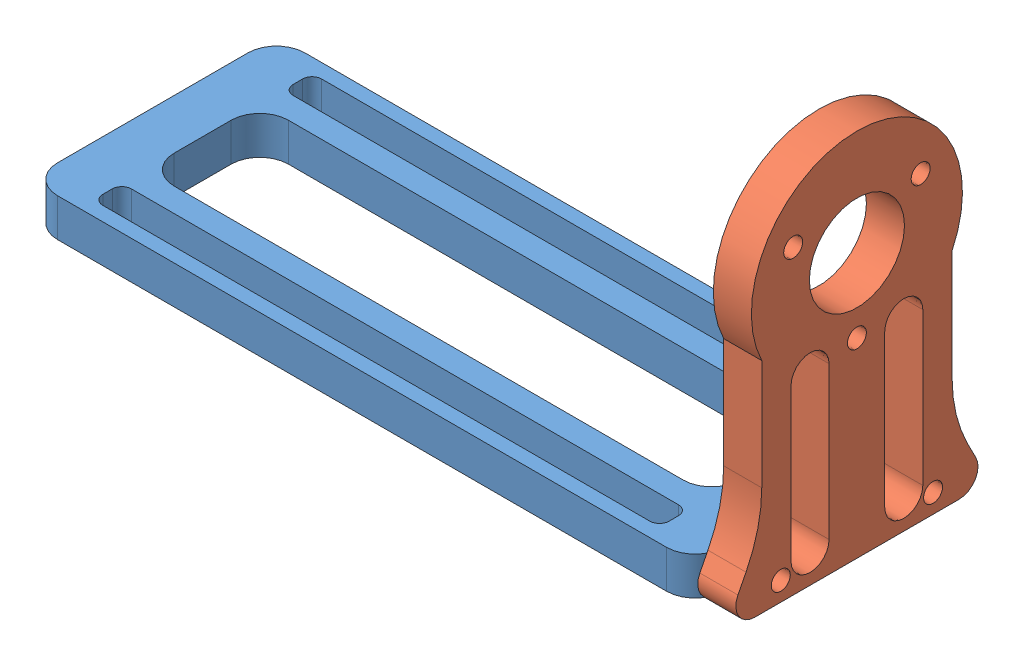
SolidWorks assembly Assem4, configuration Default. Lengths in mm.
Overall size (74 38.89 26).
2 component instances, 2 part files, 3 mates.
Components (placement in the parent):
- Camera hold-1: Camera hold [Default] at (24.9003 25.9441 60.2124) size (70 4 26)
- Motor1_below-1: Motor1_below [Default] at (59.9003 53.7377 60.2124) x (0 0 -1) z (1 0 0) size (25.45 38.89 4)
Mates (geometry in assembly coordinates):
- Concentric1: concentric: cylinder of Camera hold-1 through (54.9003 27.9441 68.2124) axis (1 0 0) radius 1; cylinder of Motor1_below-1 through (63.9003 27.9441 68.2124) axis (-1 0 0) radius 1
- Concentric2: concentric: cylinder of Camera hold-1 through (54.9003 27.9441 52.2124) axis (1 0 0) radius 1; cylinder of Motor1_below-1 through (63.9003 27.9441 52.2124) axis (-1 0 0) radius 1
- Coincident1: coincident anti-aligned: plane of Camera hold-1 through (59.9003 29.9441 70.2124) normal (1 0 0); plane of Motor1_below-1 through (59.9003 53.7377 60.2124) normal (-1 0 0)
